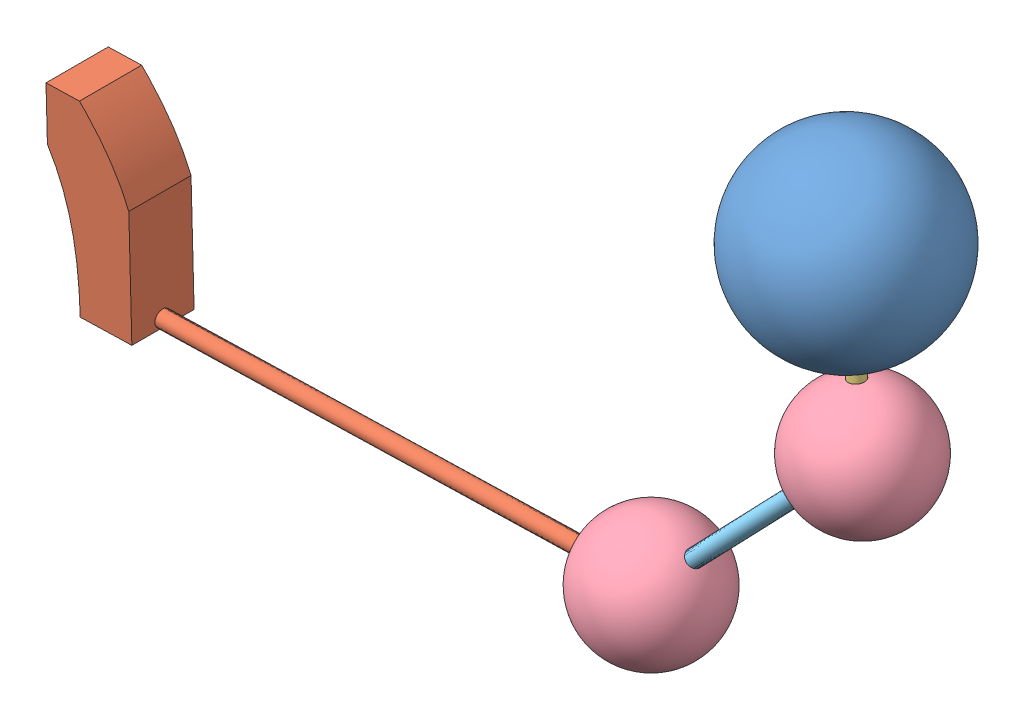
SolidWorks assembly Percy, configuration Default. Lengths in mm.
Overall size (1473.94 1000.42 380.53).
6 component instances, 5 part files, 14 mates.
Components (placement in the parent):
- head-1: head [Default] at (-39.0716 1175.0532 -12.7) x (0.696816 0.704938 -0.132325) z (-0.68738 0.70902 0.157476) size (300 300 300)
- legs-1: legs [Default] at (-452.2791 540.4108 -12.7) x (0 0 -1) z (-0.026706 0.999643 0) size (100 815 300)
- neck-1: neck [Default] at (-22.1184 995.8533 -12.7) x (-0.795298 -0.075239 -0.601532) z (0.598858 0.056655 -0.798849) size (25.4 30 25.4)
- Shoulders-1: Shoulders [Default] at (-352.3147 543.0814 -12.7) x (0.263481 -0.134568 -0.955233) z (0.724605 0.681288 0.103891) size (200 200 200)
- torso-1: torso [Default] at (-283.0056 615.1664 -12.7) x (0.554848 -0.533482 0.638389) z (-0.460182 0.442462 0.769714) size (25.4 290 25.4)
- Shoulders-2: Shoulders [Default] at (-12.7 896.2978 -12.7) size (200 200 200)
Mates (geometry in assembly coordinates):
- Tangent2: tangent anti-aligned: plane of neck-1 through (-22.1184 995.8533 -12.7) normal (0.094184 -0.995555 0); sphere of Shoulders-2
- Coincident2: coincident: point of neck-1; sphere of Shoulders-2
- Tangent4: tangent anti-aligned: sphere of head-1; plane of neck-1 through (-24.9439 1025.72 -12.7) normal (-0.094184 0.995555 0)
- Coincident4: coincident: sphere of head-1; point of neck-1
- Tangent5: tangent anti-aligned: plane of torso-1 through (-82.0091 824.2129 -12.7) normal (0.693091 0.72085 0); sphere of Shoulders-2
- Coincident5: coincident: point of torso-1; sphere of Shoulders-2
- Tangent6: tangent anti-aligned: sphere of Shoulders-1; plane of torso-1 through (-283.0056 615.1664 -12.7) normal (-0.693091 -0.72085 0)
- Coincident6: coincident: sphere of Shoulders-1; point of torso-1
- Tangent9: tangent anti-aligned: plane of legs-1 through (-452.2791 540.4108 -12.7) normal (0.999643 0.026706 0); sphere of Shoulders-1
- Coincident9: coincident: point of legs-1; sphere of Shoulders-1
- Tangent11: tangent aligned: cylinder of neck-1 through (-24.9439 1025.72 -12.7) axis (0.094184 -0.995555 0) radius 12.7; plane of assembly through (0 0 0) normal (0 0 1)
- Tangent14: tangent aligned: cylinder of legs-1 through (-1266.9884 518.6453 -12.7) axis (0.999643 0.026706 0) radius 12.7; plane of assembly through (0 0 0) normal (0 0 1)
- Tangent15: tangent aligned: cylinder of torso-1 through (-82.0091 824.2129 -12.7) axis (-0.693091 -0.72085 0) radius 12.7; plane of assembly through (0 0 0) normal (0 0 1)
- Parallel4: parallel: line of legs-1 through (-1219.6318 507.2059 -62.7) axis (0 0 1); plane of assembly
